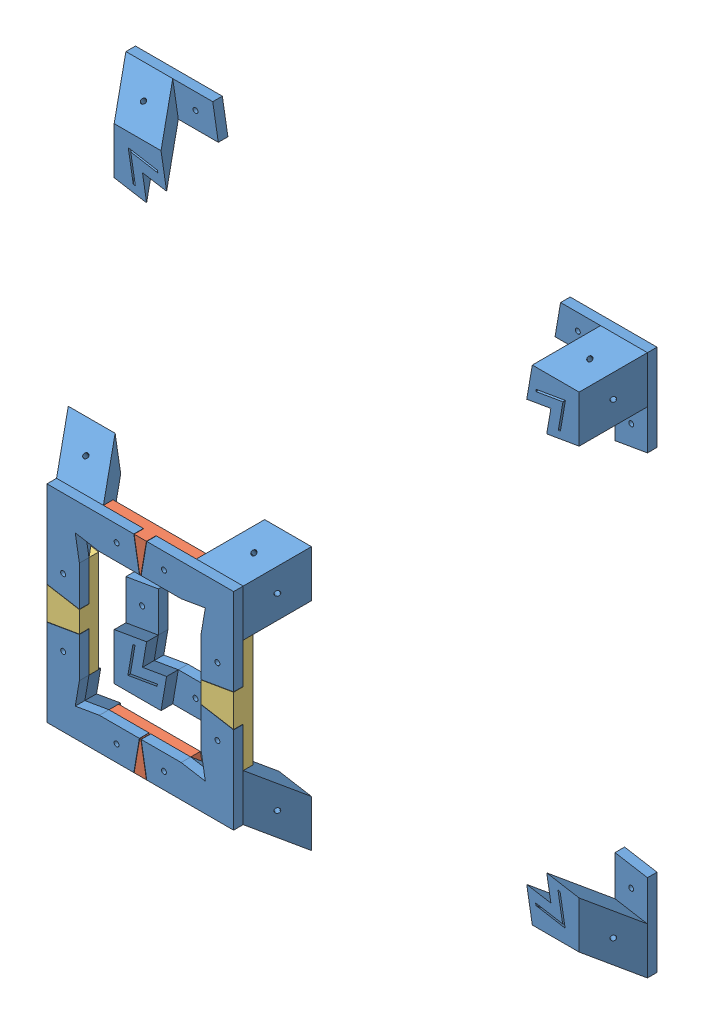
SolidWorks assembly zav-pyramide, configuration По умолчанию. Lengths in mm.
Overall size (363.39 375.89 287.91).
17 component instances, 7 part files, 46 mates.
Components (placement in the parent):
- ZAV-pyramide-surface-1: ZAV-pyramide-surface [По умолчанию] at (12.3088 359.9135 235.3104) size (326 338.5 10) (hidden)
- ZAV-pyramide-profile-support-1: ZAV-pyramide-profile-support [По умолчанию] at (-10.463 27.7822 251.3104) x (0.85353 -0.14647 -0.500033) z (0.500033 0.500033 0.70706) size (60.29 60.29 321.92)
- ZAV-pyramide-profile-support-2: ZAV-pyramide-profile-support [По умолчанию] at (315.537 366.2822 251.3104) x (-0.85353 0.14647 -0.500033) z (-0.500033 -0.500033 0.70706) size (60.29 60.29 321.92)
- ZAV-pyramide-profile-support-3: ZAV-pyramide-profile-support [По умолчанию] at (315.537 27.7822 251.3104) x (0.14647 0.85353 -0.500033) z (-0.500033 0.500033 0.70706) size (60.29 60.29 321.92)
- ZAV-pyramide-profile-support-4: ZAV-pyramide-profile-support [По умолчанию] at (-10.463 366.2822 251.3104) x (-0.14647 -0.85353 -0.500033) z (0.500033 -0.500033 0.70706) size (60.29 60.29 321.92)
- ZAV-pyramide-profile-1: ZAV-pyramide-profile [По умолчанию] at (4.7992 43.2591 260.7588) x (0.85353 -0.14647 -0.500033) z (0.500033 0.500033 0.70706) size (15 15 200) (hidden)
- ZAV-pyramide-profile-2: ZAV-pyramide-profile [По умолчанию] at (100.9356 255.0982 396.3948) x (0.85353 0.14647 -0.500033) z (-0.500033 0.500033 -0.70706) size (15 15 200) (hidden)
- ZAV-pyramide-profile-3: ZAV-pyramide-profile [По умолчанию] at (199.4977 250.0283 403.2602) x (0.14647 -0.85353 -0.500033) z (0.500033 0.500033 -0.70706) size (15 15 200) (hidden)
- ZAV-pyramide-profile-4: ZAV-pyramide-profile [По умолчанию] at (308.8998 34.2047 248.2592) x (0.14647 0.85353 -0.500033) z (-0.500033 0.500033 0.70706) size (15 15 200) (hidden)
- Деталь2-1: Деталь2 [По умолчанию] at (315.537 27.7822 251.3104) x (-0.28872 -0.866006 0.408257) z (0.816461 0 0.577401) size (293.14 273.91 2) (hidden)
- Деталь2-2: Деталь2 [По умолчанию] at (-10.463 366.2822 251.3104) x (0.28872 0.866006 0.408257) z (-0.816461 0 0.577401) size (293.14 273.91 2) (hidden)
- Деталь3-1: Деталь3 [По умолчанию] at (-10.463 27.7822 251.3104) x (-0.866006 0.28872 0.408257) z (0 -0.816461 0.577401) size (282.32 267.66 2) (hidden)
- Деталь3-2: Деталь3 [По умолчанию] at (315.537 366.2822 251.3104) x (0.866006 -0.28872 0.408257) z (0 0.816461 0.577401) size (282.32 267.66 2) (hidden)
- ZAV-pyramide-roof-brick-02-1: ZAV-pyramide-roof-brick-02 [По умолчанию] at (315.537 366.2822 399.3104) x (0.985593 -0.169133 0) z (0 0 -1) size (57.25 29.21 12)
- ZAV-pyramide-roof_brick_01-1: ZAV-pyramide-roof_brick_01 [По умолчанию] at (315.537 27.7822 399.3104) x (-0.169133 -0.985593 0) z (0 0 -1) size (69.57 31.33 12)
- ZAV-pyramide-roof_brick_01-2: ZAV-pyramide-roof_brick_01 [По умолчанию] at (-10.463 366.2822 399.3104) x (0.169133 0.985593 0) z (0 0 -1) size (69.57 31.33 12)
- ZAV-pyramide-roof-brick-02-2: ZAV-pyramide-roof-brick-02 [По умолчанию] at (-10.463 27.7822 399.3104) x (-0.985593 0.169133 0) z (0 0 -1) size (57.25 29.21 12)
Mates (geometry in assembly coordinates):
- Совпадение1: coincident anti-aligned: plane of ZAV-pyramide-surface-1 through (12.3088 359.9135 245.3104) normal (0 0 1); plane of ZAV-pyramide-profile-support-1 through (-10.463 27.7822 245.3104) normal (0 0 -1)
- Совпадение2: coincident aligned: plane of ZAV-pyramide-surface-1 through (315.537 27.7822 245.3104) normal (0 -1 0); plane of ZAV-pyramide-profile-support-1 through (-10.463 27.7822 245.3104) normal (0 -1 0)
- Совпадение3: coincident aligned: plane of ZAV-pyramide-surface-1 through (-10.463 27.7822 245.3104) normal (-1 0 0); plane of ZAV-pyramide-profile-support-1 through (-10.463 27.7822 245.3104) normal (-1 0 0)
- Совпадение4: coincident anti-aligned: plane of ZAV-pyramide-surface-1 through (12.3088 359.9135 245.3104) normal (0 0 1); plane of ZAV-pyramide-profile-support-2 through (315.537 366.2822 245.3104) normal (0 0 -1)
- Совпадение6: coincident aligned: plane of ZAV-pyramide-surface-1 through (315.537 27.7822 245.3104) normal (1 0 0); plane of ZAV-pyramide-profile-support-2 through (315.537 366.2822 245.3104) normal (1 0 0)
- Совпадение7: coincident anti-aligned: plane of ZAV-pyramide-surface-1 through (12.3088 359.9135 245.3104) normal (0 0 1); plane of ZAV-pyramide-profile-support-3 through (315.537 27.7822 245.3104) normal (0 0 -1)
- Совпадение8: coincident aligned: plane of ZAV-pyramide-surface-1 through (315.537 27.7822 245.3104) normal (1 0 0); plane of ZAV-pyramide-profile-support-3 through (315.537 27.7822 245.3104) normal (1 0 0)
- Совпадение9: coincident aligned: plane of ZAV-pyramide-surface-1 through (315.537 27.7822 245.3104) normal (0 -1 0); plane of ZAV-pyramide-profile-support-3 through (315.537 27.7822 245.3104) normal (0 -1 0)
- Совпадение10: coincident anti-aligned: plane of ZAV-pyramide-surface-1 through (12.3088 359.9135 245.3104) normal (0 0 1); plane of ZAV-pyramide-profile-support-4 through (-10.463 366.2822 245.3104) normal (0 0 -1)
- Совпадение11: coincident aligned: plane of ZAV-pyramide-surface-1 through (-10.463 27.7822 245.3104) normal (-1 0 0); plane of ZAV-pyramide-profile-support-4 through (-10.463 366.2822 245.3104) normal (-1 0 0)
- Совпадение12: coincident aligned: plane of ZAV-pyramide-surface-1 through (315.537 366.2822 245.3104) normal (0 1 0); plane of ZAV-pyramide-profile-support-4 through (-10.463 366.2822 245.3104) normal (0 1 0)
- Совпадение13: coincident aligned: plane of ZAV-pyramide-surface-1 through (315.537 366.2822 245.3104) normal (0 1 0); plane of ZAV-pyramide-profile-support-2 through (315.537 366.2822 245.3104) normal (0 1 0)
- Совпадение14: coincident anti-aligned: plane of ZAV-pyramide-profile-support-3 through (311.0864 32.0181 245.1673) normal (0.14647 0.85353 -0.500033); plane of ZAV-pyramide-profile-4 through (196.0903 132.0142 382.1707) normal (-0.14647 -0.85353 0.500033)
- Совпадение15: coincident anti-aligned: plane of ZAV-pyramide-profile-support-3 through (313.2981 44.9064 237.6168) normal (-0.85353 -0.14647 -0.500033); plane of ZAV-pyramide-profile-4 through (208.8933 134.2113 389.6712) normal (0.85353 0.14647 0.500033)
- Совпадение16: coincident anti-aligned: plane of ZAV-pyramide-profile-support-1 through (-6.2271 32.2328 245.1673) normal (0.85353 -0.14647 -0.500033); plane of ZAV-pyramide-profile-1 through (102.6088 156.0686 394.6703) normal (-0.85353 0.14647 0.500033)
- Совпадение17: coincident anti-aligned: plane of ZAV-pyramide-profile-support-1 through (6.6612 30.0211 237.6168) normal (-0.14647 0.85353 -0.500033); plane of ZAV-pyramide-profile-1 through (104.8058 143.2657 402.1708) normal (0.14647 -0.85353 0.500033)
- Совпадение18: coincident anti-aligned: plane of ZAV-pyramide-profile-support-2 through (311.3011 361.8316 245.1673) normal (-0.85353 0.14647 -0.500033); plane of ZAV-pyramide-profile-3 through (299.5043 350.0349 261.8482) normal (0.85353 -0.14647 0.500033)
- Совпадение19: coincident anti-aligned: plane of ZAV-pyramide-profile-support-2 through (298.4128 364.0433 237.6168) normal (0.14647 -0.85353 -0.500033); plane of ZAV-pyramide-profile-3 through (286.7014 352.232 254.3477) normal (-0.14647 0.85353 0.500033)
- Совпадение20: coincident anti-aligned: plane of ZAV-pyramide-profile-support-4 through (-8.2241 349.158 237.6168) normal (0.85353 0.14647 -0.500033); plane of ZAV-pyramide-profile-2 through (-1.268 342.3018 247.4823) normal (-0.85353 -0.14647 0.500033)
- Совпадение21: coincident anti-aligned: plane of ZAV-pyramide-profile-support-4 through (-6.0125 362.0463 245.1673) normal (-0.14647 -0.85353 -0.500033); plane of ZAV-pyramide-profile-2 through (0.929 355.1048 254.9828) normal (0.14647 0.85353 0.500033)
- На месте1: in place: plane of ZAV-pyramide-profile-support-3 through (165.5271 177.7921 463.4284) normal (0.816461 0 0.577401); plane of ? through (328.8136 0 232.5369) normal (0.816461 0 0.577401); moOrthogonalPlaneRef_w of ZAV-pyramide-profile-support-3 through (165.5271 177.7921 463.4284) normal (0.816461 0 0.577401); unknown of ?; plane of ZAV-pyramide-profile-support-3 through (165.5271 177.7921 463.4284) normal (0.816461 0 0.577401); plane of ? through (328.8136 0 232.5369) normal (0.577401 0 -0.816461); plane of ZAV-pyramide-profile-support-3 through (165.5271 177.7921 463.4284) normal (0.816461 0 0.577401); unknown of Деталь2-1
- Совпадение34: coincident: plane of ZAV-pyramide-profile-support-3; plane of Деталь2-1
- Совпадение35: coincident: moOrthogonalPlaneRef_w of ZAV-pyramide-profile-support-3 through (315.537 27.7822 251.3104) normal (0.500033 -0.500033 -0.70706); plane of Деталь2-1
- Совпадение36: coincident: moOrthogonalPlaneRef_w of ZAV-pyramide-profile-support-3 through (315.537 27.7822 251.3104) normal (0.28872 0.866006 -0.408257); plane of Деталь2-1
- Совпадение37: coincident: plane of ZAV-pyramide-profile-support-4 through (139.5469 216.2723 463.4284) normal (-0.816461 0 0.577401); plane of Деталь2-2 through (-10.463 366.2822 251.3104) normal (0.816461 0 -0.577401)
- Совпадение38: coincident: line of ZAV-pyramide-profile-support-4 through (94.2026 232.3265 399.3104) axis (0 1 0); line of Деталь2-2 through (94.2026 132.4478 399.3104) axis (0 1 0)
- Совпадение39: coincident: line of ZAV-pyramide-profile-support-1 through (7.217 45.4622 276.3104) axis (-0.500033 -0.500033 -0.70706); line of Деталь2-2 through (-10.463 27.7822 251.3104) axis (0.500033 0.500033 0.70706)
- На месте2: in place: plane of ZAV-pyramide-profile-support-1 through (139.5469 177.7921 463.4284) normal (0 -0.816461 0.577401); plane of ? through (0 -99.9542 70.6876) normal (0 -0.816461 0.577401); plane of ZAV-pyramide-profile-support-1 through (139.5469 177.7921 463.4284) normal (0 -0.816461 0.577401); unknown of ?; plane of ZAV-pyramide-profile-support-1 through (139.5469 177.7921 463.4284) normal (0 -0.816461 0.577401); unknown of ?; plane of ZAV-pyramide-profile-support-1 through (139.5469 177.7921 463.4284) normal (0 -0.816461 0.577401); unknown of Деталь3-1
- Совпадение40: coincident: plane of ZAV-pyramide-profile-support-1; plane of Деталь3-1
- Совпадение41: coincident: moOrthogonalPlaneRef_w of ZAV-pyramide-profile-support-1 through (-10.463 27.7822 251.3104) normal (-0.500033 -0.500033 -0.70706); plane of Деталь3-1
- Совпадение42: coincident: moOrthogonalPlaneRef_w of ZAV-pyramide-profile-support-1 through (-10.463 27.7822 251.3104) normal (0.866006 -0.28872 -0.408257); plane of Деталь3-1
- Совпадение43: coincident: plane of ZAV-pyramide-profile-support-2 through (165.5271 216.2723 463.4284) normal (0 0.816461 0.577401); plane of Деталь3-2 through (315.537 366.2822 251.3104) normal (0 -0.816461 -0.577401)
- Совпадение45: coincident: line of ZAV-pyramide-profile-support-2 through (181.5813 261.6166 399.3104) axis (1 0 0); line of Деталь3-2 through (94.2026 261.6166 399.3104) axis (1 0 0)
- Параллельность6: parallel: line of ZAV-pyramide-profile-support-2 through (210.8714 261.6166 399.3104) axis (0.500033 0.500033 -0.70706); plane of Деталь3-2 through (315.537 367.9151 252.4652) normal (0 0.816461 0.577401)
- Совпадение47: coincident: line of ZAV-pyramide-profile-support-2 through (210.8714 261.6166 399.3104) axis (0.500033 0.500033 -0.70706); line of Деталь3-2 through (210.8714 261.6166 399.3104) axis (0.500033 0.500033 -0.70706)
- На месте4: in place: plane of ZAV-pyramide-profile-support-2 through (153.1031 241.3483 399.3104) normal (0 0 -1); plane of ? through (0 0 399.3104) normal (0 0 -1); plane of ZAV-pyramide-profile-support-2 through (153.1031 241.3483 399.3104) normal (0 0 -1); unknown of ?; plane of ZAV-pyramide-profile-support-2 through (153.1031 241.3483 399.3104) normal (0 0 -1); plane of ? through (0 0 399.3104) normal (-1 0 0); plane of ZAV-pyramide-profile-support-2 through (153.1031 241.3483 399.3104) normal (0 0 -1); unknown of ZAV-pyramide-roof-brick-02-1
- Совпадение51: coincident: plane of ZAV-pyramide-profile-support-2; plane of ZAV-pyramide-roof-brick-02-1
- Совпадение52: coincident: moOrthogonalPlaneRef_w of ZAV-pyramide-profile-support-2 through (315.537 366.2822 399.3104) normal (-0.169133 -0.985593 0); plane of ZAV-pyramide-roof-brick-02-1
- Совпадение53: coincident: moOrthogonalPlaneRef_w of ZAV-pyramide-profile-support-2 through (315.537 366.2822 399.3104) normal (-0.985593 0.169133 0); plane of ZAV-pyramide-roof-brick-02-1
- Совпадение54: coincident: plane of ZAV-pyramide-profile-support-2 through (210.8714 207.3265 399.3104) normal (0 0 -1); plane of ZAV-pyramide-roof_brick_01-1 through (315.537 27.7822 399.3104) normal (0 0 1)
- Совпадение57: coincident: plane of ZAV-pyramide-profile-support-2 through (210.8714 232.3265 405.3104) normal (1 0 0); plane of ZAV-pyramide-roof_brick_01-1 through (210.8714 161.7379 393.3104) normal (1 0 0)
- Совпадение61: coincident: plane of ZAV-pyramide-profile-support-1 through (94.2026 186.7379 399.3104) normal (0 0 -1); plane of ZAV-pyramide-roof_brick_01-2 through (-10.463 366.2822 399.3104) normal (0 0 1)
- Совпадение62: coincident: plane of ZAV-pyramide-profile-support-1 through (94.2026 161.7379 405.3104) normal (-1 0 0); plane of ZAV-pyramide-roof_brick_01-2 through (94.2026 232.3265 393.3104) normal (-1 0 0)
- Совпадение64: coincident: plane of ZAV-pyramide-profile-support-1 through (151.9708 152.7161 399.3104) normal (0 0 -1); plane of ZAV-pyramide-roof-brick-02-2 through (-10.663 27.7822 399.3104) normal (0 0 1)
- Совпадение65: coincident: plane of ZAV-pyramide-profile-support-3 through (181.5813 132.4478 405.3104) normal (0 -1 0); plane of ZAV-pyramide-roof-brick-02-2 through (123.2927 132.4478 393.3104) normal (0 -1 0)
- Концентричный2: concentric: cylinder of ZAV-pyramide-profile-support-3 through (167.3422 142.5819 486.882) axis (0 0 -1) radius 1.55; cylinder of ZAV-pyramide-roof-brick-02-2 through (167.3422 142.5819 393.3104) axis (0 0 1) radius 1.55
